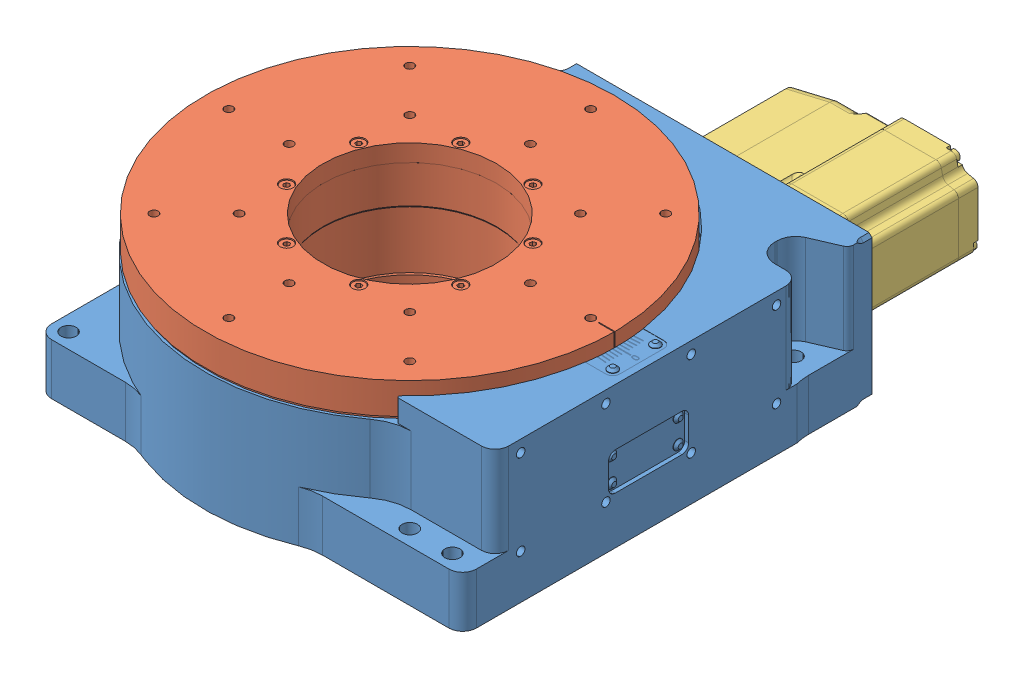
SolidWorks assembly RST240, configuration RST240x-T3A. Lengths in mm.
Overall size (260.5 90.38 337).
3 component instances, 3 part files, 6 mates.
Components (placement in the parent):
- RST240_base^RST240-1: RST240_base^RST240 [Default] at origin size (260.5 84.9 260.5) (virtual)
- RST240_top^RST240-1: RST240_top^RST240 [Default] at origin size (240 89 240) (virtual)
- NMS23_motor^RST240-1: NMS23_motor^RST240 [RST240-T3A] at (88.9 38.85 -140) size (103.96 56.4 100.5) (virtual)
Mates (geometry in assembly coordinates):
- Coincident2: coincident: point of ?
- Coincident3: coincident aligned: plane of RST240_top^RST240-1 through (0 0 0) normal (0 1 0); plane of assembly through (0 0 0) normal (0 1 0)
- Coincident5: coincident anti-aligned: plane of RST240_base^RST240-1 through (51.9 62.55 -140) normal (0 0 -1); plane of NMS23_motor^RST240-1 through (88.9 38.85 -140) normal (0 0 1)
- Concentric1: concentric: cylinder of RST240_base^RST240-1 through (88.9 38.85 -140) axis (0 0 1) radius 19.05; point of NMS23_motor^RST240-1
- Parallel1: parallel aligned: plane of NMS23_motor^RST240-1 through (88.9 38.85 -140) normal (0 1 0); plane of assembly through (0 0 0) normal (0 1 0)
- Home Position: coincident aligned: plane of RST240_top^RST240-1 through (0 0 0) normal (0 0 1); plane of assembly through (0 0 0) normal (0 0 1)
